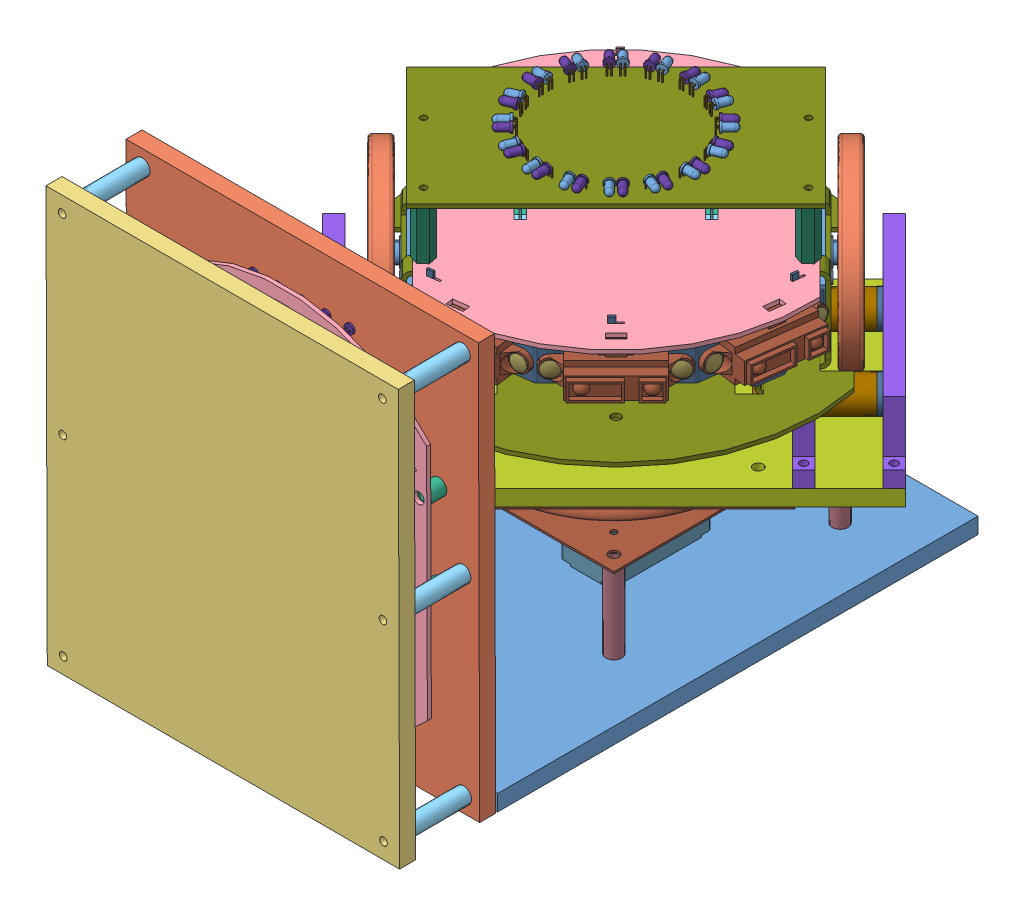
SolidWorks assembly full_station, configuration Default. Lengths in mm.
Overall size (229.02 165.32 270.36).
270 component instances, 47 part files, 51 mates.
Components (placement in the parent):
- floor-1: floor [Default] at (-21.5332 -9.2866 -56.2109) size (139.7 6.35 190.5)
- electronics_board-1: electronics_board [Default] at (-6.9858 61.8236 106.1261) x (1 -0.000582 -0.000002) z (-0.000582 -0.999993 -0.003658) size (139.7 38.1 165.1)
  - wall1-1: wall1 [Default] at (-14.5171 4.441 -69.2394) size (139.7 6.35 165.1)
  - wall2-1: wall2 [Default] at (-14.5171 36.191 -69.2394) size (139.7 6.35 165.1)
  - pcb-1: pcb [Default] at (11.8343 17.141 -8.7599) x (-1 0 0) z (0 0 -1) size (114.3 1.59 146.05)
  - wall_standoff-1: wall_standoff [Default] at (75.3343 10.791 64.781) x (1 0 0) z (0 1 0) size (6.35 6.35 25.4)
  - wall_standoff-2: wall_standoff [Default] at (75.3343 10.791 -11.419) x (1 0 0) z (0 1 0) size (6.35 6.35 25.4)
  - wall_standoff-3: wall_standoff [Default] at (-51.6657 10.791 -87.619) x (1 0 0) z (0 1 0) size (6.35 6.35 25.4)
  - wall_standoff-4: wall_standoff [Default] at (-51.6657 10.791 -11.419) x (1 0 0) z (0 1 0) size (6.35 6.35 25.4)
  - wall_standoff-5: wall_standoff [Default] at (-51.6657 10.791 64.781) x (1 0 0) z (0 1 0) size (6.35 6.35 25.4)
  - wall_standoff-6: wall_standoff [Default] at (75.3343 10.791 -87.619) x (1 0 0) z (0 1 0) size (6.35 6.35 25.4)
  - board_standoff-1: board_standoff [Default] at (65.8093 10.791 -36.5945) size (6.35 6.35 6.35)
  - board_standoff-2: board_standoff [Default] at (-42.1407 10.791 -36.5945) size (6.35 6.35 6.35)
  - board_standoff-3: board_standoff [Default] at (65.8093 10.791 -2.622) size (6.35 6.35 6.35)
  - board_standoff-4: board_standoff [Default] at (-42.1407 10.791 -2.622) size (6.35 6.35 6.35)
- dyno-1: dyno [Default] at (-38.0413 14.8235 14.9049) x (0.707107 0 -0.707107) z (0.707107 0 0.707107) size (203.2 41.47 203.2)
  - dyno_base-1: dyno_base [Default] at (-2.767 23.7054 -14.645) size (163.51 6.35 101.6)
  - dyno_block-1: dyno_block [Default] at (-36.3738 30.0554 15.23) x (0 0 -1) z (1 0 0) size (101.6 26.99 6.35)
  - dyno_block-2: dyno_block [Default] at (120.7887 30.0554 15.23) x (0 0 -1) z (1 0 0) size (101.6 26.99 6.35)
  - dyno_block-3: dyno_block [Default] at (-10.9738 30.0554 15.23) x (0 0 -1) z (1 0 0) size (101.6 26.99 6.35)
  - dyno_block-4: dyno_block [Default] at (95.3887 30.0554 15.23) x (0 0 -1) z (1 0 0) size (101.6 26.99 6.35)
  - dyno_shaft-1: dyno_shaft [Default] at (89.7827 36.0195 36.1217) x (-1 0 0) z (0 -0.049308 -0.998784) size (41.27 12.7 12.7)
  - dyno_shaft-2: dyno_shaft [Default] at (0.9822 38.9212 40.5068) x (1 0 0) z (0 0.900012 0.435865) size (41.27 12.7 12.7)
  - dyno_shaft-3: dyno_shaft [Default] at (0.9822 36.0133 -5.4075) size (41.27 12.7 12.7)
  - dyno_shaft-4: dyno_shaft [Default] at (89.7827 40.5118 -0.2947) x (-1 0 0) z (0 -0.991868 -0.127273) size (41.27 12.7 12.7)
  - dyno_bushing-1: dyno_bushing [Default] at (-4.6238 41.1679 -5.4075) x (-1 0 0) z (0 0.248835 0.968546) size (7.94 12.7 12.7)
  - dyno_bushing-2: dyno_bushing [Default] at (95.3887 41.1679 -5.4075) x (1 0 0) z (0 -0.044464 0.999011) size (7.94 12.7 12.7)
  - dyno_bushing-3: dyno_bushing [Default] at (-4.6238 41.1679 35.8675) x (-1 0 0) z (0 0.248835 0.968546) size (7.94 12.7 12.7)
  - dyno_bushing-4: dyno_bushing [Default] at (95.3887 41.1679 35.8675) x (1 0 0) z (0 -0.044464 0.999011) size (7.94 12.7 12.7)
  - dyno_bushing-5: dyno_bushing [Default] at (-36.3738 41.1679 -5.4075) size (7.94 12.7 12.7)
  - dyno_bushing-6: dyno_bushing [Default] at (-36.3738 41.1679 35.8675) size (7.94 12.7 12.7)
  - dyno_bushing-7: dyno_bushing [Default] at (127.1387 41.1679 -5.4075) x (-1 0 0) z (0 -0.924225 -0.381849) size (7.94 12.7 12.7)
  - dyno_bushing-8: dyno_bushing [Default] at (127.1387 41.1679 35.8675) x (-1 0 0) z (0 -0.924225 -0.381849) size (7.94 12.7 12.7)
  - turntable-1: turntable [Default] at (45.3824 20.4034 15.23) x (0.707107 0 -0.707107) z (0.707107 0 0.707107) size (143.68 8.13 143.68)
  - encoder-1: encoder [Default] at (95.3887 41.1679 -5.4075) x (-1 0 0) z (0 -0.047032 -0.998893) size (11.51 21.64 22.89)
  - encoder-2: encoder [Default] at (-4.6238 41.1679 -5.4075) x (1 0 0) z (0 -0.069358 -0.997592) size (11.51 21.64 22.89)
- turntable_standoff-1: turntable_standoff [Default] at (49.6619 30.4009 38.4276) x (0.999128 0 -0.041762) z (0 -1 0) size (6.35 6.35 33.34)
- turntable_standoff-2: turntable_standoff [Default] at (49.6619 30.4009 -51.2598) x (0.999128 0 -0.041762) z (0 -1 0) size (6.35 6.35 33.34)
- turntable_standoff-3: turntable_standoff [Default] at (-40.0255 30.4009 -51.2598) x (0.999128 0 -0.041762) z (0 -1 0) size (6.35 6.35 33.34)
- turntable_standoff-4: turntable_standoff [Default] at (-40.0255 30.4009 38.4276) x (0.999128 0 -0.041762) z (0 -1 0) size (6.35 6.35 33.34)
- Hitec Servo-1: Hitec Servo [Default] at (69.4085 38.4634 7.4887) x (0 0 1) z (-1 0 0) size (52.8 41.4 20)
  - Hitec Servo-1: Hitec Servo [Default] at (-9.6529 -41.4 51.51) x (1 0 0) z (0 1 0) size (52.8 20 41.4)
  - servo gear - 36t-1: servo gear - 36t [Default] at (-19.6529 -3.175 51.51) size (19.05 3.17 19.05)
- colonybot-1: colonybot [Default] at (5.2495 73.9 -6.8473) x (0.707107 0 -0.707107) z (0.707107 0 0.707107) size (161.93 92.14 161.95)
  - base-2: base [Default] x (-1 0 0) z (0 0 -1) size (133.35 40.56 158.75)
    - base-1: base [Default] at origin size (133.35 33.72 158.75)
    - PEM_PHA-M4-8-1: PEM_PHA-M4-8 [Default] at (0 0 63.5) size (5.9 8 5.9)
    - mmc94808A130-1: mmc94808A130 [Default] at (-52.3875 32.131 -27.8346) x (-1 0 0) z (0 0 -1) size (6.35 3.96 9.4)
    - mmc94808A130-2: mmc94808A130 [Default] at (-52.3875 32.131 6.1379) size (6.35 3.96 9.4)
    - mmc94808A130-3: mmc94808A130 [Default] at (52.3875 32.131 -27.8346) x (-1 0 0) z (0 0 -1) size (6.35 3.96 9.4)
    - mmc94808A130-4: mmc94808A130 [Default] at (52.3875 32.131 6.1379) size (6.35 3.96 9.4)
  - pcb-2: pcb [Default] at (0 32.5628 0) size (114.3 5.84 146.05)
    - pcb-1: pcb [Default] at origin size (114.3 1.59 146.05)
    - ESE11MH1-1: ESE11MH1 [Default] at (1.65 -2.125 37.1312) x (-1 0 0) z (0 0 1) size (6.4 4.75 8.75)
    - ESE11MH1-2: ESE11MH1 [Default] at (-1.65 -2.125 51.7688) x (1 0 0) z (0 0 -1) size (6.4 4.75 8.75)
  - gm8-1: gm8 [Default] at (42.8625 27.369 -10.1061) x (1 0 0) z (0 0.000053 -1) size (55.69 22.61 47.43)
  - gm8-2: gm8 [Default] at (-42.8625 4.763 -10.1073) x (-1 0 0) z (0 0.000053 -1) size (55.69 22.61 47.43)
  - gm8_wheel-1: gm8_wheel [Default] at (-65.913 16.0655 0) x (-1 0 0) z (0 -0.453451 -0.891281) size (7.52 66.8 66.8)
  - gm8_wheel-2: gm8_wheel [Default] at (65.913 16.0655 0) x (1 0 0) z (0 0.453451 0.891281) size (7.52 66.8 66.8)
  - enc-magnet-1: enc-magnet [Default] at (-34.7067 17.9166 0.878) x (0 0.798106 -0.602517) z (1 0 0) size (7.94 7.94 9.89)
    - enc-magnetholder-1: enc-magnetholder [Default] at (-0.9483 -1.8161 1.7342) size (7.94 7.94 9.89)
    - encoder_magnet-1: encoder_magnet [Default] at (-0.9483 -1.8161 -0.7658) size (6 6 2.5)
  - enc-magnet-2: enc-magnet [Default] at (34.7067 14.1936 0.8327) x (0 -0.783207 -0.621761) z (-1 0 0) size (7.94 7.94 9.89)
    - enc-magnetholder-1: enc-magnetholder [Default] at (-0.9483 -1.8161 1.7342) size (7.94 7.94 9.89)
    - encoder_magnet-1: encoder_magnet [Default] at (-0.9483 -1.8161 -0.7658) size (6 6 2.5)
  - encoder_board-1: encoder_board [left] at (30.1625 27.368 10.0361) x (0 0.000053 -1) z (0 1 0.000053) size (20.57 7.07 26.54)
  - encoder_board-2: encoder_board [right] at (-30.1625 4.762 10.0349) x (0 0.000053 -1) z (0 -1 -0.000053) size (20.57 7.07 26.54)
  - battery_asm-1: battery_asm [Default] at (0 -1.5875 -30.1625) size (60.32 32.64 76.2)
    - battery_cover-1: battery_cover [Default] x (-1 0 0) z (0 0 -1) size (60.32 3.18 76.2)
    - mmc93625K258-1: mmc93625K258 [Default] at (0 0 4.7625) size (38.1 3.17 44.45)
    - AA5cel-2: AA5cel [Default] at (0 8.8375 4.7625) x (0 0 1) z (-1 0 0) size (49.5 27.06 43.5)
      - AAcell-1: AAcell [Default] x (0 1 0) z (0 0 1) size (14.5 49.5 14.5)
      - AAcell-2: AAcell [Default] at (0 0 -14.5) x (0 1 0) z (0 0 1) size (14.5 49.5 14.5)
      - AAcell-3: AAcell [Default] at (0 0 14.5) x (0 -1 0) z (0 0 1) size (14.5 49.5 14.5)
      - AAcell-4: AAcell [Default] at (0 12.5574 -7.25) x (0 -1 0) z (0 0 1) size (14.5 49.5 14.5)
      - AAcell-5: AAcell [Default] at (0 12.5574 7.25) x (0 -1 0) z (0 0 1) size (14.5 49.5 14.5)
    - battery_strap-1: battery_strap [Default] at (0 -0.7937 4.7625) size (47.62 32.64 19.05)
  - front_IR-1: front_IR [Default] at (0 20.1628 59.436) size (133.17 32.99 43.68)
    - IR_mount-1: IR_mount [Default] at origin size (116.48 32.99 27.85)
    - gp2d12-1: gp2d12 [Default] at (0 0 0.7937) x (-1 0 0) z (0 0 1) size (44.5 18.9 13.5)
    - gp2d12-2: gp2d12 [Default] at (-40.7168 0 -12.982) x (-0.793353 0 -0.608761) z (-0.608761 0 0.793353) size (44.5 18.9 13.5)
    - gp2d12-3: gp2d12 [Default] at (40.7168 0 -12.982) x (-0.793353 0 0.608761) z (0.608761 0 0.793353) size (44.5 18.9 13.5)
    - mmc90136A465-1: mmc90136A465 [Default] at (-18.5 0 2.7937) x (1 0 0) z (0 -1 0) size (6.35 6.08 6.35)
    - mmc90136A465-2: mmc90136A465 [Default] at (56.6114 0 -22.6574) x (0.62941 -0.608761 -0.482963) z (-0.482963 -0.793353 0.37059) size (6.35 6.08 6.35)
    - mmc90136A465-4: mmc90136A465 [Default] at (-27.2573 0 -0.1332) x (0.62941 0.608761 0.482963) z (0.482963 -0.793353 0.37059) size (6.35 6.08 6.35)
    - mmc90136A465-5: mmc90136A465 [Default] at (27.2573 0 -0.1332) x (0.62941 -0.608761 -0.482963) z (-0.482963 -0.793353 0.37059) size (6.35 6.08 6.35)
    - mmc90136A465-6: mmc90136A465 [Default] at (18.5 0 2.7937) x (1 0 0) z (0 -1 0) size (6.35 6.08 6.35)
    - mmc90136A465-7: mmc90136A465 [Default] at (-56.6114 0 -22.6574) x (0.62941 0.608761 0.482963) z (0.482963 -0.793353 0.37059) size (6.35 6.08 6.35)
  - rear_IR-1: rear_IR [Default] at (0 20.1628 -70.8836) size (90.5 32.99 45.45)
    - rear_IR_mount-1: rear_IR_mount [Default] at origin size (63.5 32.99 45.42)
    - gp2d12-1: gp2d12 [Default] at (31.75 0 22.225) x (0 0 1) z (1 0 0) size (44.5 18.9 13.5)
    - gp2d12-2: gp2d12 [Default] at (-31.75 0 22.225) x (0 0 -1) z (-1 0 0) size (44.5 18.9 13.5)
    - mmc90136A465-1: mmc90136A465 [Default] at (-33.75 0 40.725) x (0 1 0) z (0 0 1) size (6.35 6.08 6.35)
    - mmc90136A465-2: mmc90136A465 [Default] at (33.75 0 3.725) x (0 -1 0) z (0 0 1) size (6.35 6.08 6.35)
    - mmc90136A465-3: mmc90136A465 [Default] at (-33.75 0 3.725) x (0 1 0) z (0 0 1) size (6.35 6.08 6.35)
    - mmc90136A465-4: mmc90136A465 [Default] at (33.75 0 40.725) x (0 -1 0) z (0 0 1) size (6.35 6.08 6.35)
  - 4NB83C-1: 4NB83C [Default] at (0 -2.3813 -63.5) size (16.07 15 16.07)
  - shell-1: shell [Default] at (0 3.5719 0) size (161.93 69.85 161.95) (hidden)
  - standoff-1: standoff [Default] at (-30.7987 34.1503 19.2964) size (7.33 28.58 6.58)
  - standoff-2: standoff [Default] at (-30.7987 34.1503 53.2689) size (7.33 28.58 6.58)
  - standoff-3: standoff [Default] at (77.1513 34.1503 19.2964) size (7.33 28.58 6.58)
  - standoff-4: standoff [Default] at (77.1513 34.1503 53.2689) size (7.33 28.58 6.58)
  - BOM-1: BOM [Default] at (-12.6128 44.3165 0.3627) x (-1 0 0) z (0 0 -1) size (117.47 6.92 69.57)
    - BOM board-1: BOM board [Default] at (-36.729 12.0588 -12.709) size (117.47 1.57 66.67)
    - purple LED-1: purple LED [Default] at (18.4661 16.6759 -2.8499) x (-1 0 0) z (0 0 -1) size (7.1 6.92 3.66)
      - purple LED-1: purple LED [Default] at (36.6225 0.4703 11.8376) size (5.83 3.66 3.66)
      - led lead-1: led lead [Default] at (1.8689 0.4629 -0.5367) x (0 1 0) z (-1 0 0) size (5.33 0.51 1.52)
      - led lead-2: led lead [Default] at (1.8689 0.4629 0.7333) x (0 1 0) z (-1 0 0) size (5.33 0.51 1.52)
    - purple LED-2: purple LED [Default] at (10.6408 16.6759 19.6554) x (-0.707107 0 -0.707107) z (0.707107 0 -0.707107) size (7.1 6.92 3.66)
      - purple LED-1: purple LED [Default] at (36.6225 0.4703 11.8376) size (5.83 3.66 3.66)
      - led lead-1: led lead [Default] at (1.8689 0.4629 -0.5367) x (0 1 0) z (-1 0 0) size (5.33 0.51 1.52)
      - led lead-2: led lead [Default] at (1.8689 0.4629 0.7333) x (0 1 0) z (-1 0 0) size (5.33 0.51 1.52)
    - purple LED-3: purple LED [Default] at (16.7917 16.6759 9.181) x (-0.92388 0 -0.382683) z (0.382683 0 -0.92388) size (7.1 6.92 3.66)
      - purple LED-1: purple LED [Default] at (36.6225 0.4703 11.8376) size (5.83 3.66 3.66)
      - led lead-1: led lead [Default] at (1.8689 0.4629 -0.5367) x (0 1 0) z (-1 0 0) size (5.33 0.51 1.52)
      - led lead-2: led lead [Default] at (1.8689 0.4629 0.7333) x (0 1 0) z (-1 0 0) size (5.33 0.51 1.52)
    - purple LED-4: purple LED [Default] at (15.4089 16.6759 -14.6057) x (-0.92388 0 0.382683) z (-0.382683 0 -0.92388) size (7.1 6.92 3.66)
      - purple LED-1: purple LED [Default] at (36.6225 0.4703 11.8376) size (5.83 3.66 3.66)
      - led lead-1: led lead [Default] at (1.8689 0.4629 -0.5367) x (0 1 0) z (-1 0 0) size (5.33 0.51 1.52)
      - led lead-2: led lead [Default] at (1.8689 0.4629 0.7333) x (0 1 0) z (-1 0 0) size (5.33 0.51 1.52)
    - purple LED-5: purple LED [Default] at (-26.1754 16.6759 -29.0649) x (0.382683 0 0.92388) z (-0.92388 0 0.382683) size (7.1 6.92 3.66)
      - purple LED-1: purple LED [Default] at (36.6225 0.4703 11.8376) size (5.83 3.66 3.66)
      - led lead-1: led lead [Default] at (1.8689 0.4629 -0.5367) x (0 1 0) z (-1 0 0) size (5.33 0.51 1.52)
      - led lead-2: led lead [Default] at (1.8689 0.4629 0.7333) x (0 1 0) z (-1 0 0) size (5.33 0.51 1.52)
    - purple LED-6: purple LED [Default] at (-42.0173 16.6759 -11.2674) x (0.92388 0 0.382683) z (-0.382683 0 0.92388) size (7.1 6.92 3.66)
      - purple LED-1: purple LED [Default] at (36.6225 0.4703 11.8376) size (5.83 3.66 3.66)
      - led lead-1: led lead [Default] at (1.8689 0.4629 -0.5367) x (0 1 0) z (-1 0 0) size (5.33 0.51 1.52)
      - led lead-2: led lead [Default] at (1.8689 0.4629 0.7333) x (0 1 0) z (-1 0 0) size (5.33 0.51 1.52)
    - purple LED-7: purple LED [Default] at (-35.8664 16.6759 -21.7418) x (0.707107 0 0.707107) z (-0.707107 0 0.707107) size (7.1 6.92 3.66)
      - purple LED-1: purple LED [Default] at (36.6225 0.4703 11.8376) size (5.83 3.66 3.66)
      - led lead-1: led lead [Default] at (1.8689 0.4629 -0.5367) x (0 1 0) z (-1 0 0) size (5.33 0.51 1.52)
      - led lead-2: led lead [Default] at (1.8689 0.4629 0.7333) x (0 1 0) z (-1 0 0) size (5.33 0.51 1.52)
    - purple LED-8: purple LED [Default] at (-14.4195 16.6759 -32.1221) x (0 0 1) z (-1 0 0) size (7.1 6.92 3.66)
      - purple LED-1: purple LED [Default] at (36.6225 0.4703 11.8376) size (5.83 3.66 3.66)
      - led lead-1: led lead [Default] at (1.8689 0.4629 -0.5367) x (0 1 0) z (-1 0 0) size (5.33 0.51 1.52)
      - led lead-2: led lead [Default] at (1.8689 0.4629 0.7333) x (0 1 0) z (-1 0 0) size (5.33 0.51 1.52)
    - purple LED-9: purple LED [Default] at (8.0858 16.6759 -24.2968) x (-0.707107 0 0.707107) z (-0.707107 0 -0.707107) size (7.1 6.92 3.66)
      - purple LED-1: purple LED [Default] at (36.6225 0.4703 11.8376) size (5.83 3.66 3.66)
      - led lead-1: led lead [Default] at (1.8689 0.4629 -0.5367) x (0 1 0) z (-1 0 0) size (5.33 0.51 1.52)
      - led lead-2: led lead [Default] at (1.8689 0.4629 0.7333) x (0 1 0) z (-1 0 0) size (5.33 0.51 1.52)
    - purple LED-10: purple LED [Default] at (-43.6917 16.6759 0.7635) size (7.1 6.92 3.66)
      - purple LED-1: purple LED [Default] at (36.6225 0.4703 11.8376) size (5.83 3.66 3.66)
      - led lead-1: led lead [Default] at (1.8689 0.4629 -0.5367) x (0 1 0) z (-1 0 0) size (5.33 0.51 1.52)
      - led lead-2: led lead [Default] at (1.8689 0.4629 0.7333) x (0 1 0) z (-1 0 0) size (5.33 0.51 1.52)
    - purple LED-11: purple LED [Default] at (-40.6346 16.6759 12.5193) x (0.92388 0 -0.382683) z (0.382683 0 0.92388) size (7.1 6.92 3.66)
      - purple LED-1: purple LED [Default] at (36.6225 0.4703 11.8376) size (5.83 3.66 3.66)
      - led lead-1: led lead [Default] at (1.8689 0.4629 -0.5367) x (0 1 0) z (-1 0 0) size (5.33 0.51 1.52)
      - led lead-2: led lead [Default] at (1.8689 0.4629 0.7333) x (0 1 0) z (-1 0 0) size (5.33 0.51 1.52)
    - purple LED-12: purple LED [Default] at (-33.3114 16.6759 22.2104) x (0.707107 0 -0.707107) z (0.707107 0 0.707107) size (7.1 6.92 3.66)
      - purple LED-1: purple LED [Default] at (36.6225 0.4703 11.8376) size (5.83 3.66 3.66)
      - led lead-1: led lead [Default] at (1.8689 0.4629 -0.5367) x (0 1 0) z (-1 0 0) size (5.33 0.51 1.52)
      - led lead-2: led lead [Default] at (1.8689 0.4629 0.7333) x (0 1 0) z (-1 0 0) size (5.33 0.51 1.52)
    - purple LED-13: purple LED [Default] at (-2.3886 16.6759 -30.4477) x (-0.382683 0 0.92388) z (-0.92388 0 -0.382683) size (7.1 6.92 3.66)
      - purple LED-1: purple LED [Default] at (36.6225 0.4703 11.8376) size (5.83 3.66 3.66)
      - led lead-1: led lead [Default] at (1.8689 0.4629 -0.5367) x (0 1 0) z (-1 0 0) size (5.33 0.51 1.52)
      - led lead-2: led lead [Default] at (1.8689 0.4629 0.7333) x (0 1 0) z (-1 0 0) size (5.33 0.51 1.52)
    - purple LED-14: purple LED [Default] at (-22.837 16.6759 28.3613) x (0.382683 0 -0.92388) z (0.92388 0 0.382683) size (7.1 6.92 3.66)
      - purple LED-1: purple LED [Default] at (36.6225 0.4703 11.8376) size (5.83 3.66 3.66)
      - led lead-1: led lead [Default] at (1.8689 0.4629 -0.5367) x (0 1 0) z (-1 0 0) size (5.33 0.51 1.52)
      - led lead-2: led lead [Default] at (1.8689 0.4629 0.7333) x (0 1 0) z (-1 0 0) size (5.33 0.51 1.52)
    - purple LED-15: purple LED [Default] at (-10.8061 16.6759 30.0357) x (0 0 -1) z (1 0 0) size (7.1 6.92 3.66)
      - purple LED-1: purple LED [Default] at (36.6225 0.4703 11.8376) size (5.83 3.66 3.66)
      - led lead-1: led lead [Default] at (1.8689 0.4629 -0.5367) x (0 1 0) z (-1 0 0) size (5.33 0.51 1.52)
      - led lead-2: led lead [Default] at (1.8689 0.4629 0.7333) x (0 1 0) z (-1 0 0) size (5.33 0.51 1.52)
    - purple LED-16: purple LED [Default] at (0.9497 16.6759 26.9786) x (-0.382683 0 -0.92388) z (0.92388 0 -0.382683) size (7.1 6.92 3.66)
      - purple LED-1: purple LED [Default] at (36.6225 0.4703 11.8376) size (5.83 3.66 3.66)
      - led lead-1: led lead [Default] at (1.8689 0.4629 -0.5367) x (0 1 0) z (-1 0 0) size (5.33 0.51 1.52)
      - led lead-2: led lead [Default] at (1.8689 0.4629 0.7333) x (0 1 0) z (-1 0 0) size (5.33 0.51 1.52)
    - black LED-3: black LED [Default] at (9.0529 16.9166 22.8429) x (-0.707107 0 -0.707107) z (0.707107 0 -0.707107) size (7.1 6.92 3.66)
      - black LED-1: black LED [Default] at (37.7537 0.2295 11.4043) size (5.83 3.66 3.66)
      - led lead-1: led lead [Default] at (3 0.2221 -0.97) x (0 1 0) z (-1 0 0) size (5.33 0.51 1.52)
      - led lead-2: led lead [Default] at (3 0.2221 0.3) x (0 1 0) z (-1 0 0) size (5.33 0.51 1.52)
    - black LED-4: black LED [Default] at (16.5445 16.9166 12.7335) x (-0.92388 0 -0.382683) z (0.382683 0 -0.92388) size (7.1 6.92 3.66)
      - black LED-1: black LED [Default] at (37.7537 0.2295 11.4043) size (5.83 3.66 3.66)
      - led lead-1: led lead [Default] at (3 0.2221 -0.97) x (0 1 0) z (-1 0 0) size (5.33 0.51 1.52)
      - led lead-2: led lead [Default] at (3 0.2221 0.3) x (0 1 0) z (-1 0 0) size (5.33 0.51 1.52)
    - black LED-5: black LED [Default] at (19.5972 16.9166 0.5268) x (-1 0 0) z (0 0 -1) size (7.1 6.92 3.66)
      - black LED-1: black LED [Default] at (37.7537 0.2295 11.4043) size (5.83 3.66 3.66)
      - led lead-1: led lead [Default] at (3 0.2221 -0.97) x (0 1 0) z (-1 0 0) size (5.33 0.51 1.52)
      - led lead-2: led lead [Default] at (3 0.2221 0.3) x (0 1 0) z (-1 0 0) size (5.33 0.51 1.52)
    - black LED-6: black LED [Default] at (17.7462 16.9166 -11.9189) x (-0.92388 0 0.382683) z (-0.382683 0 -0.92388) size (7.1 6.92 3.66)
      - black LED-1: black LED [Default] at (37.7537 0.2295 11.4043) size (5.83 3.66 3.66)
      - led lead-1: led lead [Default] at (3 0.2221 -0.97) x (0 1 0) z (-1 0 0) size (5.33 0.51 1.52)
      - led lead-2: led lead [Default] at (3 0.2221 0.3) x (0 1 0) z (-1 0 0) size (5.33 0.51 1.52)
    - black LED-7: black LED [Default] at (-41.7702 16.9166 -14.8199) x (0.92388 0 0.382683) z (-0.382683 0 0.92388) size (7.1 6.92 3.66)
      - black LED-1: black LED [Default] at (37.7537 0.2295 11.4043) size (5.83 3.66 3.66)
      - led lead-1: led lead [Default] at (3 0.2221 -0.97) x (0 1 0) z (-1 0 0) size (5.33 0.51 1.52)
      - led lead-2: led lead [Default] at (3 0.2221 0.3) x (0 1 0) z (-1 0 0) size (5.33 0.51 1.52)
    - black LED-8: black LED [Default] at (1.1639 16.9166 -30.2005) x (-0.382683 0 0.92388) z (-0.92388 0 -0.382683) size (7.1 6.92 3.66)
      - black LED-1: black LED [Default] at (37.7537 0.2295 11.4043) size (5.83 3.66 3.66)
      - led lead-1: led lead [Default] at (3 0.2221 -0.97) x (0 1 0) z (-1 0 0) size (5.33 0.51 1.52)
      - led lead-2: led lead [Default] at (3 0.2221 0.3) x (0 1 0) z (-1 0 0) size (5.33 0.51 1.52)
    - black LED-9: black LED [Default] at (11.2733 16.9166 -22.7089) x (-0.707107 0 0.707107) z (-0.707107 0 -0.707107) size (7.1 6.92 3.66)
      - black LED-1: black LED [Default] at (37.7537 0.2295 11.4043) size (5.83 3.66 3.66)
      - led lead-1: led lead [Default] at (3 0.2221 -0.97) x (0 1 0) z (-1 0 0) size (5.33 0.51 1.52)
      - led lead-2: led lead [Default] at (3 0.2221 0.3) x (0 1 0) z (-1 0 0) size (5.33 0.51 1.52)
    - black LED-10: black LED [Default] at (-11.0428 16.9166 -33.2532) x (0 0 1) z (-1 0 0) size (7.1 6.92 3.66)
      - black LED-1: black LED [Default] at (37.7537 0.2295 11.4043) size (5.83 3.66 3.66)
      - led lead-1: led lead [Default] at (3 0.2221 -0.97) x (0 1 0) z (-1 0 0) size (5.33 0.51 1.52)
      - led lead-2: led lead [Default] at (3 0.2221 0.3) x (0 1 0) z (-1 0 0) size (5.33 0.51 1.52)
    - black LED-11: black LED [Default] at (-23.4885 16.9166 -31.4022) x (0.382683 0 0.92388) z (-0.92388 0 0.382683) size (7.1 6.92 3.66)
      - black LED-1: black LED [Default] at (37.7537 0.2295 11.4043) size (5.83 3.66 3.66)
      - led lead-1: led lead [Default] at (3 0.2221 -0.97) x (0 1 0) z (-1 0 0) size (5.33 0.51 1.52)
      - led lead-2: led lead [Default] at (3 0.2221 0.3) x (0 1 0) z (-1 0 0) size (5.33 0.51 1.52)
    - black LED-12: black LED [Default] at (-34.2786 16.9166 -24.9293) x (0.707107 0 0.707107) z (-0.707107 0 0.707107) size (7.1 6.92 3.66)
      - black LED-1: black LED [Default] at (37.7537 0.2295 11.4043) size (5.83 3.66 3.66)
      - led lead-1: led lead [Default] at (3 0.2221 -0.97) x (0 1 0) z (-1 0 0) size (5.33 0.51 1.52)
      - led lead-2: led lead [Default] at (3 0.2221 0.3) x (0 1 0) z (-1 0 0) size (5.33 0.51 1.52)
    - black LED-13: black LED [Default] at (-44.8228 16.9166 -2.6132) size (7.1 6.92 3.66)
      - black LED-1: black LED [Default] at (37.7537 0.2295 11.4043) size (5.83 3.66 3.66)
      - led lead-1: led lead [Default] at (3 0.2221 -0.97) x (0 1 0) z (-1 0 0) size (5.33 0.51 1.52)
      - led lead-2: led lead [Default] at (3 0.2221 0.3) x (0 1 0) z (-1 0 0) size (5.33 0.51 1.52)
    - black LED-14: black LED [Default] at (-1.7371 16.9166 29.3158) x (-0.382683 0 -0.92388) z (0.92388 0 -0.382683) size (7.1 6.92 3.66)
      - black LED-1: black LED [Default] at (37.7537 0.2295 11.4043) size (5.83 3.66 3.66)
      - led lead-1: led lead [Default] at (3 0.2221 -0.97) x (0 1 0) z (-1 0 0) size (5.33 0.51 1.52)
      - led lead-2: led lead [Default] at (3 0.2221 0.3) x (0 1 0) z (-1 0 0) size (5.33 0.51 1.52)
    - black LED-15: black LED [Default] at (-42.9718 16.9166 9.8325) x (0.92388 0 -0.382683) z (0.382683 0 0.92388) size (7.1 6.92 3.66)
      - black LED-1: black LED [Default] at (37.7537 0.2295 11.4043) size (5.83 3.66 3.66)
      - led lead-1: led lead [Default] at (3 0.2221 -0.97) x (0 1 0) z (-1 0 0) size (5.33 0.51 1.52)
      - led lead-2: led lead [Default] at (3 0.2221 0.3) x (0 1 0) z (-1 0 0) size (5.33 0.51 1.52)
    - black LED-16: black LED [Default] at (-36.4989 16.9166 20.6225) x (0.707107 0 -0.707107) z (0.707107 0 0.707107) size (7.1 6.92 3.66)
      - black LED-1: black LED [Default] at (37.7537 0.2295 11.4043) size (5.83 3.66 3.66)
      - led lead-1: led lead [Default] at (3 0.2221 -0.97) x (0 1 0) z (-1 0 0) size (5.33 0.51 1.52)
      - led lead-2: led lead [Default] at (3 0.2221 0.3) x (0 1 0) z (-1 0 0) size (5.33 0.51 1.52)
    - black LED-17: black LED [Default] at (-26.3896 16.9166 28.1141) x (0.382683 0 -0.92388) z (0.92388 0 0.382683) size (7.1 6.92 3.66)
      - black LED-1: black LED [Default] at (37.7537 0.2295 11.4043) size (5.83 3.66 3.66)
      - led lead-1: led lead [Default] at (3 0.2221 -0.97) x (0 1 0) z (-1 0 0) size (5.33 0.51 1.52)
      - led lead-2: led lead [Default] at (3 0.2221 0.3) x (0 1 0) z (-1 0 0) size (5.33 0.51 1.52)
    - black LED-18: black LED [Default] at (-14.1828 16.9166 31.1668) x (0 0 -1) z (1 0 0) size (7.1 6.92 3.66)
      - black LED-1: black LED [Default] at (37.7537 0.2295 11.4043) size (5.83 3.66 3.66)
      - led lead-1: led lead [Default] at (3 0.2221 -0.97) x (0 1 0) z (-1 0 0) size (5.33 0.51 1.52)
      - led lead-2: led lead [Default] at (3 0.2221 0.3) x (0 1 0) z (-1 0 0) size (5.33 0.51 1.52)
  - charge_board_heatsink-1: charge_board_heatsink [Default] at (26.9875 17.7815 -70.8836) x (0 1 0) z (-1 0 0) size (13.36 4.66 50.8)
  - homing_beacon_mount-1: homing_beacon_mount [Default] at (7.9375 0 -79.375) x (0 0 1) z (-1 0 0) size (25.4 10.5 15.88)
  - charge_board-2: charge_board [Default] at (11.8961 17.2791 -66.2799) x (-1 0 0) z (0 1 0) size (54.56 1.57 27.03)
- swivel_hinge-1: swivel_hinge [Default] at (26.5148 4.7494 92.1019) x (1 0 0) z (0 -0.003658 0.999993) size (25.4 25.4 30.96)
- hinge-1: hinge [Default] at (18.9693 -17.7734 85.7471) size (6.35 12.7 25.4)
- hinge-2: hinge [Default] at (-9.3328 -17.7734 111.1471) x (-1 0 0) z (0 0 -1) size (6.35 12.7 25.4)
- hinge_bushing-1: hinge_bushing [Default] at (-15.8193 8.1482 98.9599) x (1 0 0) z (0 -0.107676 0.994186) size (7.94 12.7 12.7)
- hinge_bushing-2: hinge_bushing [Default] at (25.4557 5.5607 102.698) x (-1 0 0) z (0 0.892587 -0.450875) size (7.94 12.7 12.7)
- hinge_shaft-1: hinge_shaft [Default] at (-15.8193 3.4134 98.4471) x (1 0 0) z (0 -0.107676 0.994186) size (41.27 9.53 9.53)
- black LED-1: black LED [Default] at (4.4881 135.2484 114.6937) x (0 -0.003658 0.999993) z (-0.88627 0.463166 0.001694) size (7.1 6.92 3.66)
  - black LED-1: black LED [Default] at (37.7537 0.2295 11.4043) size (5.83 3.66 3.66)
  - led lead-1: led lead [Default] at (3 0.2221 -0.97) x (0 1 0) z (-1 0 0) size (5.33 0.51 1.52)
  - led lead-2: led lead [Default] at (3 0.2221 0.3) x (0 1 0) z (-1 0 0) size (5.33 0.51 1.52)
- purple LED-1: purple LED [Default] at (-13.764 135.0298 115.824) x (0 -0.003658 0.999993) z (-0.726053 -0.687634 -0.002515) size (7.1 6.92 3.66)
  - purple LED-1: purple LED [Default] at (36.6225 0.4703 11.8376) size (5.83 3.66 3.66)
  - led lead-1: led lead [Default] at (1.8689 0.4629 -0.5367) x (0 1 0) z (-1 0 0) size (5.33 0.51 1.52)
  - led lead-2: led lead [Default] at (1.8689 0.4629 0.7333) x (0 1 0) z (-1 0 0) size (5.33 0.51 1.52)
- purple LED-2: purple LED [Default] at (-4.7644 134.8358 115.8233) x (0 -0.003658 0.999993) z (-0.88627 0.463166 0.001694) size (7.1 6.92 3.66)
  - purple LED-1: purple LED [Default] at (36.6225 0.4703 11.8376) size (5.83 3.66 3.66)
  - led lead-1: led lead [Default] at (1.8689 0.4629 -0.5367) x (0 1 0) z (-1 0 0) size (5.33 0.51 1.52)
  - led lead-2: led lead [Default] at (1.8689 0.4629 0.7333) x (0 1 0) z (-1 0 0) size (5.33 0.51 1.52)
- purple LED-3: purple LED [Default] at (14.2856 134.8247 115.8232) x (0 -0.003658 0.999993) z (-0.88627 0.463166 0.001694) size (7.1 6.92 3.66)
  - purple LED-1: purple LED [Default] at (36.6225 0.4703 11.8376) size (5.83 3.66 3.66)
  - led lead-1: led lead [Default] at (1.8689 0.4629 -0.5367) x (0 1 0) z (-1 0 0) size (5.33 0.51 1.52)
  - led lead-2: led lead [Default] at (1.8689 0.4629 0.7333) x (0 1 0) z (-1 0 0) size (5.33 0.51 1.52)
- purple LED-4: purple LED [Default] at (23.8106 134.8191 115.8232) x (0 -0.003658 0.999993) z (-0.88627 0.463166 0.001694) size (7.1 6.92 3.66)
  - purple LED-1: purple LED [Default] at (36.6225 0.4703 11.8376) size (5.83 3.66 3.66)
  - led lead-1: led lead [Default] at (1.8689 0.4629 -0.5367) x (0 1 0) z (-1 0 0) size (5.33 0.51 1.52)
  - led lead-2: led lead [Default] at (1.8689 0.4629 0.7333) x (0 1 0) z (-1 0 0) size (5.33 0.51 1.52)
- purple LED-5: purple LED [Default] at (11.0782 79.0851 115.6194) x (0 -0.003658 0.999993) z (-0.88627 0.463166 0.001694) size (7.1 6.92 3.66)
  - purple LED-1: purple LED [Default] at (36.6225 0.4703 11.8376) size (5.83 3.66 3.66)
  - led lead-1: led lead [Default] at (1.8689 0.4629 -0.5367) x (0 1 0) z (-1 0 0) size (5.33 0.51 1.52)
  - led lead-2: led lead [Default] at (1.8689 0.4629 0.7333) x (0 1 0) z (-1 0 0) size (5.33 0.51 1.52)
- purple LED-6: purple LED [Default] at (-1.6218 79.0925 115.6194) x (0 -0.003658 0.999993) z (-0.88627 0.463166 0.001694) size (7.1 6.92 3.66)
  - purple LED-1: purple LED [Default] at (36.6225 0.4703 11.8376) size (5.83 3.66 3.66)
  - led lead-1: led lead [Default] at (1.8689 0.4629 -0.5367) x (0 1 0) z (-1 0 0) size (5.33 0.51 1.52)
  - led lead-2: led lead [Default] at (1.8689 0.4629 0.7333) x (0 1 0) z (-1 0 0) size (5.33 0.51 1.52)
- servo gear - 18t-1: servo gear - 18t [Default] at (4.8182 35.3539 -6.4161) size (9.53 3.17 9.53)
Mates (geometry in assembly coordinates):
- Concentric1: concentric aligned: cylinder of dyno-1/turntable-1; cylinder of turntable_standoff-1
- Coincident6: coincident anti-aligned: plane of dyno-1/turntable-1 through (4.8182 30.4009 -52.8434) normal (0 -1 0); plane of turntable_standoff-1 through (49.6619 30.4009 38.4276) normal (0 1 0)
- Concentric2: concentric aligned: cylinder of dyno-1/turntable-1; cylinder of turntable_standoff-2
- Coincident7: coincident anti-aligned: plane of dyno-1/turntable-1 through (4.8182 30.4009 -52.8434) normal (0 -1 0); plane of turntable_standoff-2 through (49.6619 30.4009 -51.2598) normal (0 1 0)
- Concentric4: concentric aligned: cylinder of dyno-1/turntable-1; cylinder of turntable_standoff-3
- Coincident9: coincident anti-aligned: plane of dyno-1/turntable-1 through (4.8182 30.4009 -52.8434) normal (0 -1 0); plane of turntable_standoff-3 through (-40.0255 30.4009 -51.2598) normal (0 1 0)
- Concentric6: concentric aligned: cylinder of dyno-1/turntable-1; cylinder of turntable_standoff-4
- Coincident11: coincident anti-aligned: plane of dyno-1/turntable-1 through (4.8182 30.4009 -52.8434) normal (0 -1 0); plane of turntable_standoff-4 through (-40.0255 30.4009 38.4276) normal (0 1 0)
- Concentric7: concentric anti-aligned: cylinder of floor-1; cylinder of turntable_standoff-1
- Concentric8: concentric anti-aligned: cylinder of floor-1; cylinder of turntable_standoff-4
- Coincident12: coincident anti-aligned: plane of floor-1 through (-65.0318 -2.9366 109.5596) normal (0 1 0); plane of turntable_standoff-1 through (49.6619 -2.9366 38.4276) normal (0 -1 0)
- Coincident13: coincident anti-aligned: plane of floor-1 through (-65.0318 -2.9366 109.5596) normal (0 1 0); plane of Hitec Servo-1/Hitec Servo-1 through (7.7234 -2.9366 19.0108) normal (0 -1 0)
- Parallel1: parallel aligned: line of floor-1; line of Hitec Servo-1/Hitec Servo-1
- Tangent5: tangent anti-aligned: cylinder of dyno-1/dyno_shaft-4; cylinder of colonybot-1/gm8_wheel-2
- Parallel2: parallel aligned: plane of dyno-1/dyno_block-2 through (98.5497 44.8789 -28.3055) normal (0.707107 0 -0.707107); plane of colonybot-1/gm8_wheel-2 through (45.2046 115.796 -65.3876) normal (0.707107 0 -0.707107)
- Tangent6: tangent anti-aligned: cylinder of dyno-1/dyno_shaft-1; cylinder of colonybot-1/gm8_wheel-2
- Tangent7: tangent anti-aligned: cylinder of dyno-1/dyno_shaft-2; cylinder of colonybot-1/gm8_wheel-1
- Parallel3: parallel: line of dyno-1/dyno_block-4; plane of colonybot-1/base-2/base-1 through (-26.1814 72.3125 -119.1005) normal (0 -1 0)
- Concentric9: concentric aligned: cylinder of electronics_board-1/wall1-1; cylinder of swivel_hinge-1
- Coincident14: coincident anti-aligned: plane of electronics_board-1/wall1-1 through (-65.0428 -9.2894 110.307) normal (0 0.003658 -0.999993); plane of swivel_hinge-1 through (-7.8818 -2.9801 110.33) normal (0 -0.003658 0.999993)
- Concentric11: concentric aligned: cylinder of hinge-1; cylinder of hinge_bushing-1
- Coincident30: coincident anti-aligned: plane of hinge-1 through (-9.4693 9.7634 111.1471) normal (1 0 0); plane of hinge_bushing-1 through (-9.4693 3.664 98.4742) normal (-1 0 0)
- Concentric12: concentric aligned: cylinder of hinge-2; cylinder of hinge_bushing-2
- Coincident31: coincident anti-aligned: plane of hinge-2 through (19.1057 9.7634 85.7471) normal (-1 0 0); plane of hinge_bushing-2 through (19.1057 3.5271 98.6721) normal (1 0 0)
- Concentric13: concentric aligned: cylinder of hinge_bushing-1; cylinder of hinge_shaft-1
- Coincident32: coincident anti-aligned: plane of hinge_bushing-1 through (-7.8818 3.664 98.4742) normal (1 0 0); plane of hinge_shaft-1 through (-7.8818 6.57 98.789) normal (-1 0 0)
- Concentric14: concentric aligned: cylinder of swivel_hinge-1; cylinder of hinge_shaft-1
- Coincident33: coincident anti-aligned: plane of swivel_hinge-1 through (-7.8818 22.4197 110.4229) normal (-1 0 0); plane of hinge_bushing-1 through (-7.8818 3.664 98.4742) normal (1 0 0)
- Concentric16: concentric anti-aligned: cylinder of floor-1; cylinder of hinge-2
- Concentric17: concentric anti-aligned: cylinder of floor-1; cylinder of hinge-2
- Coincident34: coincident anti-aligned: plane of floor-1 through (-65.0318 -2.9366 109.5596) normal (0 1 0); plane of hinge-2 through (25.4557 -2.9366 85.7471) normal (0 -1 0)
- Concentric19: concentric anti-aligned: cylinder of floor-1; cylinder of hinge-1
- Concentric20: concentric anti-aligned: cylinder of floor-1; cylinder of hinge-1
- Coincident35: coincident anti-aligned: plane of floor-1 through (-65.0318 -2.9366 109.5596) normal (0 1 0); plane of hinge-1 through (-15.8193 -2.9366 111.1471) normal (0 -1 0)
- Concentric21: concentric anti-aligned: cylinder of electronics_board-1/wall1-1; cylinder of purple LED-1/purple LED-1
- Coincident37: coincident anti-aligned: plane of electronics_board-1/wall1-1 through (-65.0428 -9.3126 116.6569) normal (0 -0.003658 0.999993); plane of purple LED-1/purple LED-1 through (-13.0983 136.3029 117.1895) normal (0 0.003658 -0.999993)
- Concentric22: concentric anti-aligned: cylinder of electronics_board-1/wall1-1; cylinder of black LED-1/black LED-1
- Coincident38: coincident anti-aligned: plane of electronics_board-1/wall1-1 through (-65.0428 -9.3126 116.6569) normal (0 -0.003658 0.999993); plane of black LED-1/black LED-1 through (6.1857 134.6111 117.1833) normal (0 0.003658 -0.999993)
- Concentric23: concentric anti-aligned: cylinder of electronics_board-1/wall1-1; cylinder of purple LED-2/purple LED-1
- Coincident39: coincident anti-aligned: plane of electronics_board-1/wall1-1 through (-65.0428 -9.3126 116.6569) normal (0 -0.003658 0.999993); plane of purple LED-2/purple LED-1 through (-3.3393 134.6167 117.1834) normal (0 0.003658 -0.999993)
- Concentric24: concentric anti-aligned: cylinder of electronics_board-1/wall1-1; cylinder of purple LED-3/purple LED-1
- Coincident40: coincident anti-aligned: plane of electronics_board-1/wall1-1 through (-65.0428 -9.3126 116.6569) normal (0 -0.003658 0.999993); plane of purple LED-3/purple LED-1 through (15.7107 134.6056 117.1833) normal (0 0.003658 -0.999993)
- Concentric25: concentric anti-aligned: cylinder of electronics_board-1/wall1-1; cylinder of purple LED-4/purple LED-1
- Coincident41: coincident anti-aligned: plane of electronics_board-1/wall1-1 through (-65.0428 -9.3126 116.6569) normal (0 -0.003658 0.999993); plane of purple LED-4/purple LED-1 through (25.2357 134.6 117.1833) normal (0 0.003658 -0.999993)
- Concentric26: concentric anti-aligned: circle of electronics_board-1/wall1-1; cylinder of purple LED-5/purple LED-1
- Coincident42: coincident anti-aligned: plane of electronics_board-1/wall1-1 through (-65.0428 -9.3126 116.6569) normal (0 -0.003658 0.999993); plane of purple LED-5/purple LED-1 through (12.5033 78.866 116.9794) normal (0 0.003658 -0.999993)
- Concentric27: concentric anti-aligned: cylinder of electronics_board-1/wall1-1; cylinder of purple LED-6/purple LED-1
- Coincident43: coincident anti-aligned: plane of electronics_board-1/wall1-1 through (-65.0428 -9.3126 116.6569) normal (0 -0.003658 0.999993); plane of purple LED-6/purple LED-1 through (-0.1967 78.8734 116.9795) normal (0 0.003658 -0.999993)
- Concentric28: concentric anti-aligned: cylinder of dyno-1/dyno_base-1; cylinder of servo gear - 18t-1
- Coincident45: coincident anti-aligned: plane of dyno-1/dyno_base-1 through (-88.9132 38.5289 15.4733) normal (0 -1 0); plane of servo gear - 18t-1 through (4.8182 38.5289 -6.4161) normal (0 1 0)
- Tangent8: tangent anti-aligned: cylinder of Hitec Servo-1/servo gear - 36t-1; cylinder of servo gear - 18t-1
